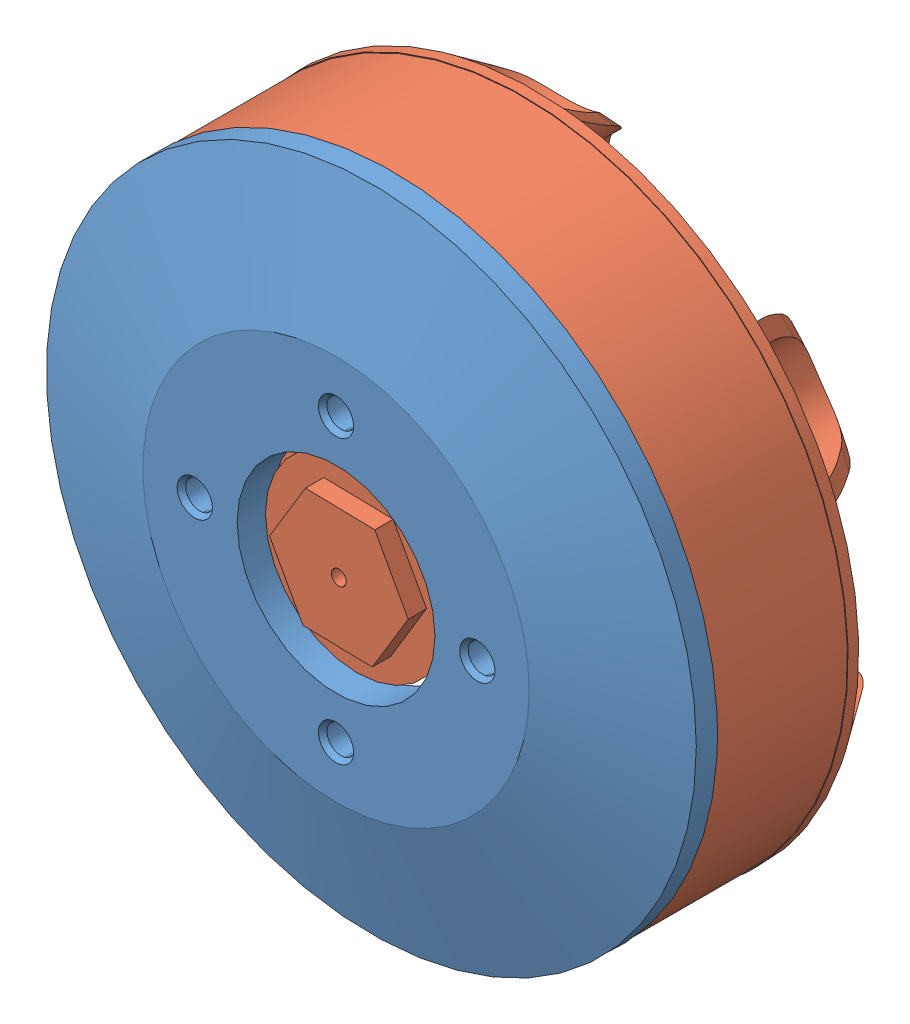
SolidWorks assembly 9235Assemblage, configuration Défaut. Lengths in mm.
Overall size (122.95 122.95 44.9).
2 component instances, 2 part files, 2 mates.
Components (placement in the parent):
- 9235Flasque-1: 9235Flasque [Défaut] at (19.2387 3.3166 -4) size (92 92 8)
- 9235Cage-1: 9235Cage [Défaut] at (19.2387 3.3166 -4) x (-0.436935 -0.899493 0) z (0 0 -1) size (92 92 44.5)
Mates (geometry in assembly coordinates):
- Coaxiale1: concentric anti-aligned: cylinder of 9235Flasque-1 through (19.2387 3.3166 -1) axis (0 0 -1) radius 46; cylinder of 9235Cage-1 through (19.2387 3.3166 -34) axis (0 0 1) radius 46
- Coïncidente1: coincident anti-aligned: plane of 9235Flasque-1 through (19.2387 3.3166 -4) normal (0 0 -1); plane of 9235Cage-1 through (19.2387 3.3166 -4) normal (0 0 1)
